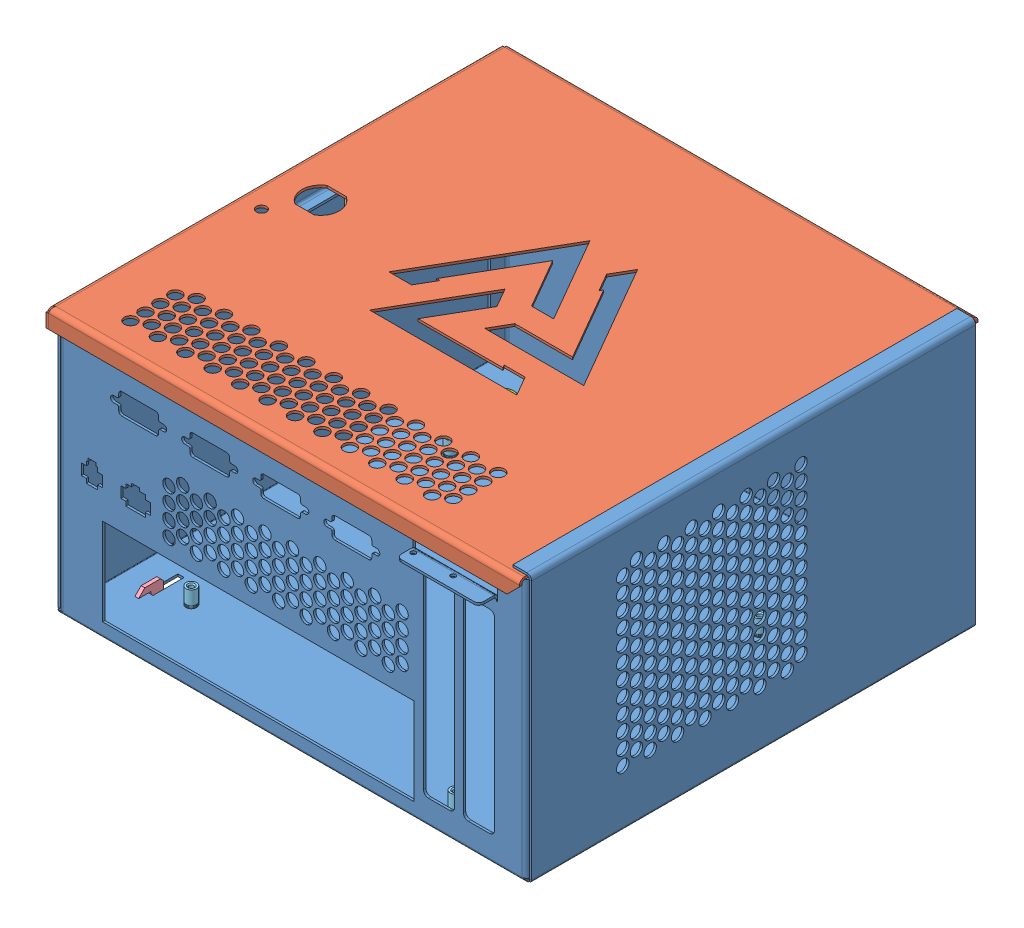
SolidWorks assembly CPU Box, configuration Default. Lengths in mm.
Overall size (243.73 142.81 240.03).
12 component instances, 8 part files, 27 mates.
Components (placement in the parent):
- Enclosure_Base-1: Enclosure_Base [Default] at (-155.6186 -50.875 116.6815) size (241.3 135.83 237.55)
- Enclosure_Lid-1: Enclosure_Lid [Default] at (83.1973 83.6892 -111.9185) x (0 0 1) z (1 0 0) size (233.57 9.53 241.25)
- Cherry_Bracket_2-1: Cherry_Bracket_2 [Default] at (-154.4045 47.55 -29.3685) x (0 0 -1) z (1 0 0) size (63.5 26.61 26.61)
- Mount Up-1: Mount Up [Default] at (66.6314 -55.955 -88.4794) x (-1 0 0) z (0 0 -1) size (208.9 12.7 180.97)
- 375 standoff BSO-632-12ZI-1: 375 standoff BSO-632-12ZI [Default] at (34.6455 -50.24 103.1992) x (0 -1 0) z (0 0 1) size (9.53 6.35 7.33)
- 375 standoff BSO-632-12ZI-2: 375 standoff BSO-632-12ZI [Default] at (34.6455 -50.24 -51.7408) x (0 -1 0) z (-0.547319 0 0.836924) size (9.53 6.35 7.33)
- 375 standoff BSO-632-12ZI-3: 375 standoff BSO-632-12ZI [Default] at (-122.8345 -50.24 80.3392) x (0 -1 0) z (0 0 1) size (9.53 6.35 7.33)
- 375 standoff BSO-632-12ZI-4: 375 standoff BSO-632-12ZI [Default] at (-122.8345 -50.24 -51.7408) x (0 -1 0) z (0 0 1) size (9.53 6.35 7.33)
- Cherry stud FH-632-6ZI-1: Cherry stud FH-632-6ZI [Default] at (-155.6186 57.075 -35.7185) x (1 0 0) z (0 0 -1) size (9.53 5.23 5.23)
- Cherry stud FH-632-6ZI-2: Cherry stud FH-632-6ZI [Default] at (-155.6186 57.075 -86.5185) x (1 0 0) z (0 0 -1) size (9.53 5.23 5.23)
- Thumbscrew PF11-832-0-1: Thumbscrew PF11-832-0 [Default] at (-123.8686 -49.6608 -78.9544) x (1 0 0) z (0 1 0) size (13.06 13.06 17.27)
- Thumbscrew standoff CSS-832-3-1: Thumbscrew standoff CSS-832-3 [Default] at (-123.8686 -55.955 -78.9544) x (0 1 0) z (0.963598 0 0.267356) size (5.8 8.74 9.17)
Mates (geometry in assembly coordinates):
- Coincident6: coincident anti-aligned: plane of Enclosure_Base-1 through (-154.4045 82.475 -111.9185) normal (1 0 0); plane of Cherry_Bracket_2-1 through (-154.4045 72.95 -29.3685) normal (-1 0 0)
- Coincident14: coincident anti-aligned: plane of Enclosure_Base-1 through (-136.5686 -50.875 86.1456) normal (0 0 -1); plane of Mount Up-1
- Coincident15: coincident aligned: plane of Enclosure_Base-1 through (-155.6186 -50.875 -111.9185) normal (0 -1 0); plane of Mount Up-1 through (69.4813 -50.875 92.4956) normal (0 -1 0)
- Concentric12: concentric anti-aligned: cylinder of Cherry_Bracket_2-1 through (-153.1903 57.075 -86.5185) axis (-1 0 0) radius 2.0638; cylinder of Enclosure_Base-1 through (-162.8028 57.075 -86.5185) axis (1 0 0) radius 1.7399
- Concentric13: concentric anti-aligned: cylinder of Enclosure_Base-1 through (-162.8028 57.075 -35.7185) axis (1 0 0) radius 1.7399; cylinder of Cherry_Bracket_2-1 through (-153.1903 57.075 -35.7185) axis (-1 0 0) radius 2.0638
- Concentric14: concentric anti-aligned: cylinder of Enclosure_Base-1 through (-122.8345 -50.875 80.3392) axis (0 1 0) radius 2.7051; cylinder of 375 standoff BSO-632-12ZI-3 through (-122.8345 -45.4775 80.3392) axis (0 -1 0) radius 2.6924
- Coincident16: coincident aligned: plane of 375 standoff BSO-632-12ZI-3 through (-122.8345 -50.875 80.3392) normal (0 -1 0); plane of Enclosure_Base-1 through (-155.6186 -50.875 -111.9185) normal (0 -1 0)
- Concentric15: concentric anti-aligned: cylinder of Enclosure_Base-1 through (34.6455 -50.875 103.1992) axis (0 1 0) radius 2.7051; cylinder of 375 standoff BSO-632-12ZI-1 through (34.6455 -45.4775 103.1992) axis (0 -1 0) radius 2.6924
- Coincident17: coincident aligned: plane of 375 standoff BSO-632-12ZI-1 through (34.6455 -50.875 103.1992) normal (0 -1 0); plane of Enclosure_Base-1 through (-155.6186 -50.875 -111.9185) normal (0 -1 0)
- Concentric16: concentric anti-aligned: cylinder of Enclosure_Base-1 through (34.6455 -50.875 -51.7408) axis (0 1 0) radius 2.7051; cylinder of 375 standoff BSO-632-12ZI-2 through (34.6455 -45.4775 -51.7408) axis (0 -1 0) radius 2.6924
- Coincident18: coincident aligned: plane of 375 standoff BSO-632-12ZI-2 through (34.6455 -50.875 -51.7408) normal (0 -1 0); plane of Enclosure_Base-1 through (-155.6186 -50.875 -111.9185) normal (0 -1 0)
- Concentric19: concentric anti-aligned: cylinder of Enclosure_Base-1 through (-122.8345 -50.875 -51.7408) axis (0 1 0) radius 2.7051; cylinder of 375 standoff BSO-632-12ZI-4 through (-122.8345 -45.4775 -51.7408) axis (0 -1 0) radius 2.6924
- Coincident20: coincident aligned: plane of 375 standoff BSO-632-12ZI-4 through (-122.8345 -50.875 -51.7408) normal (0 -1 0); plane of Enclosure_Base-1 through (-155.6186 -50.875 -111.9185) normal (0 -1 0)
- Concentric20: concentric aligned: cylinder of Cherry_Bracket_2-1 through (-153.1903 57.075 -86.5185) axis (-1 0 0) radius 2.0638; cylinder of Cherry stud FH-632-6ZI-2 through (-150.8307 57.075 -86.5185) axis (-1 0 0) radius 1.7526
- Coincident21: coincident aligned: plane of Cherry stud FH-632-6ZI-2 through (-155.6186 57.075 -87.6958) normal (-1 0 0); plane of Enclosure_Base-1 through (-155.6186 82.475 -111.9185) normal (-1 0 0)
- Concentric21: concentric anti-aligned: cylinder of Enclosure_Base-1 through (-162.8028 57.075 -35.7185) axis (1 0 0) radius 1.7399; cylinder of Cherry stud FH-632-6ZI-1 through (-150.8307 57.075 -35.7185) axis (-1 0 0) radius 1.7526
- Coincident22: coincident aligned: plane of Cherry stud FH-632-6ZI-1 through (-155.6186 57.075 -36.8958) normal (-1 0 0); plane of Enclosure_Base-1 through (-155.6186 82.475 -111.9185) normal (-1 0 0)
- Concentric22: concentric aligned: cylinder of Enclosure_Base-1 through (-123.8686 -50.875 -78.9544) axis (0 1 0) radius 3.9624; cylinder of Mount Up-1 through (-123.8686 -57.8523 -78.9544) axis (0 1 0) radius 3.9624
- Concentric23: concentric anti-aligned: cylinder of Mount Up-1 through (-123.8686 -57.8523 -78.9544) axis (0 1 0) radius 3.9624; cylinder of Thumbscrew standoff CSS-832-3-1 through (-123.8686 -53.6148 -78.9544) axis (0 -1 0) radius 3.1115
- Coincident24: coincident aligned: plane of Mount Up-1 through (65.8677 -55.955 -98.4769) normal (0 1 0); plane of Thumbscrew standoff CSS-832-3-1 through (-124.4818 -55.955 -76.7443) normal (0 1 0)
- Concentric24: concentric anti-aligned: cylinder of Enclosure_Base-1 through (-123.8686 -50.875 -78.9544) axis (0 1 0) radius 3.9624; cylinder of Thumbscrew PF11-832-0-1 through (-123.8686 -52.3456 -78.9544) axis (0 -1 0) radius 2.0828
- Coincident25: coincident anti-aligned: plane of Enclosure_Base-1 through (-155.6186 -49.6608 -111.9185) normal (0 1 0); plane of Thumbscrew PF11-832-0-1 through (-118.9727 -49.6608 -78.9544) normal (0 -1 0)
- Coincident26: coincident aligned: line of Enclosure_Base-1 through (-151.9185 82.475 -111.9185) axis (1 0 0); line of Enclosure_Lid-1 through (-155.5627 82.475 -111.9185) axis (1 0 0)
- Parallel1: parallel anti-aligned: plane of Enclosure_Base-1 through (85.6814 82.475 -111.9185) normal (0 1 0); plane of Enclosure_Lid-1 through (-155.5627 82.475 -111.9185) normal (0 -1 0)
- Coincident28: coincident anti-aligned: line of Enclosure_Base-1 through (83.1973 83.745 115.4656) axis (0 0 -1); plane of Enclosure_Lid-1 through (83.1973 82.475 -111.9185) normal (1 0 0)
- Coincident29: coincident anti-aligned: plane of Enclosure_Base-1 through (-155.6186 -50.875 -111.9185) normal (0 -1 0); plane of Mount Up-1 through (78.2238 -50.875 82.0983) normal (0 1 0)
- Width2: width aligned: plane of Enclosure_Base-1 through (-139.7436 -50.875 70.2706) normal (1 0 0); plane of Enclosure_Base-1 through (69.8064 -50.875 70.2706) normal (-1 0 0); plane of Mount Up-1 through (69.4813 -55.955 -88.4794) normal (1 0 0); plane of Mount Up-1 through (-139.4185 -55.955 -88.4794) normal (-1 0 0)
